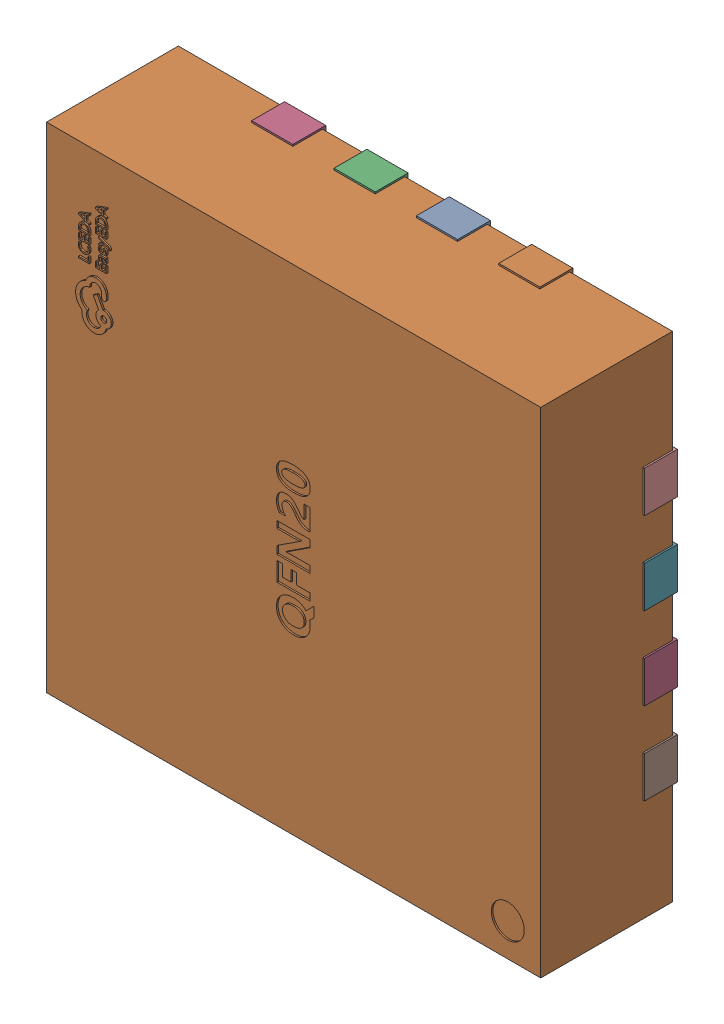
SolidWorks assembly EFM8SB10F8G-A-QFN20, configuration Défaut. Lengths in mm.
Overall size (3.02 3.02 0.83).
3 component instances, 1 part files, 0 mates.
Components (placement in the parent):
- U1.step_167-1: U1.step_167 [Défaut] at (5.0775 -6.7805 1.6001) size (3.02 3.02 0.83)
  - QFN-20_L3.0-W3.0-P0.50-BL-EP1.7_EFM8BB21F16G.step-1: QFN-20_L3.0-W3.0-P0.50-BL-EP1.7_EFM8BB21F16G.step [Défaut] at origin size (3.02 3.02 0.83)
    - COMPOUND.step_169-1: COMPOUND.step_169 [Défaut] at origin size (3.02 3.02 0.83)
